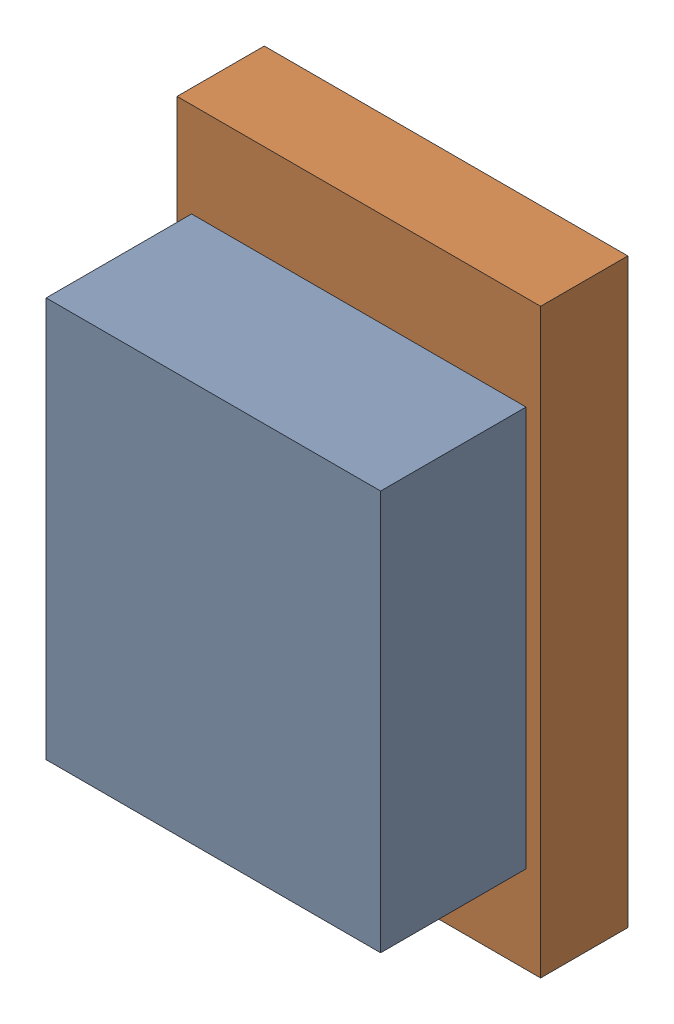
SolidWorks assembly LED2_Motor_6Kanaloa_v2.0.0_Loko, configuration Default. Lengths in mm.
Overall size (1.25 2 0.8).
4 component instances, 2 part files, 0 mates.
Components (placement in the parent):
- 334788912-1: 334788912 [Default] at (72.7202 79.2355 0) size (1.15 1.38 0.8)
  - Extruded_31-1: Extruded_31 [Default] at origin size (1.15 1.38 0.8)
- 425429200-1: 425429200 [Default] at (72.7202 79.248 0) size (1.25 2 0.3)
  - Extruded_32-1: Extruded_32 [Default] at origin size (1.25 2 0.3)
